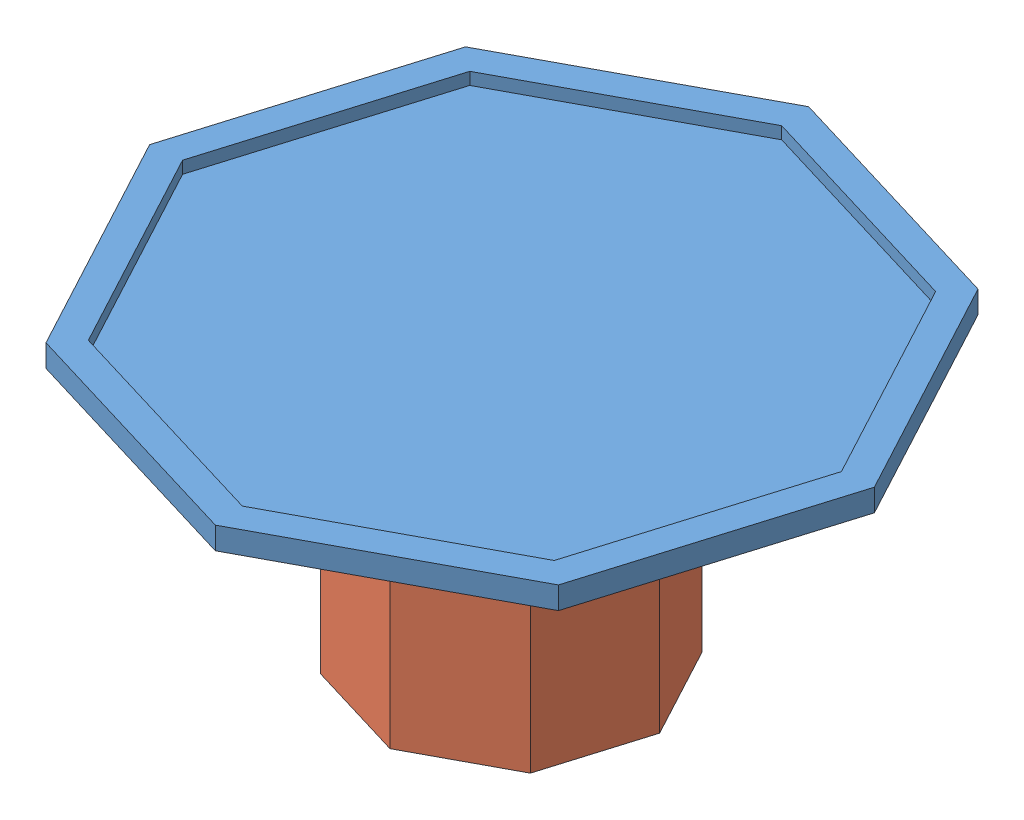
SolidWorks assembly Baugruppe1, configuration Standard. Lengths in mm.
Overall size (1184.76 540 1184.76).
2 component instances, 2 part files, 3 mates.
Components (placement in the parent):
- platte-1: platte [Standard] at (-10.1215 85.4327 0) size (1184.76 40 1184.76)
- tischsockel-1: tischsockel [Standard] at (-10.1215 -414.5673 1.1372) size (484.67 500 484.67)
Mates (geometry in assembly coordinates):
- Deckungsgleich1: coincident anti-aligned: plane of platte-1 through (-1278.8364 85.4327 -51.7615) normal (0 -1 0); plane of tischsockel-1 through (-529.2248 85.4327 -20.0379) normal (0 1 0)
- Deckungsgleich2: coincident aligned: line of platte-1; line of tischsockel-1
- Parallel1: parallel aligned: line of platte-1; line of tischsockel-1
